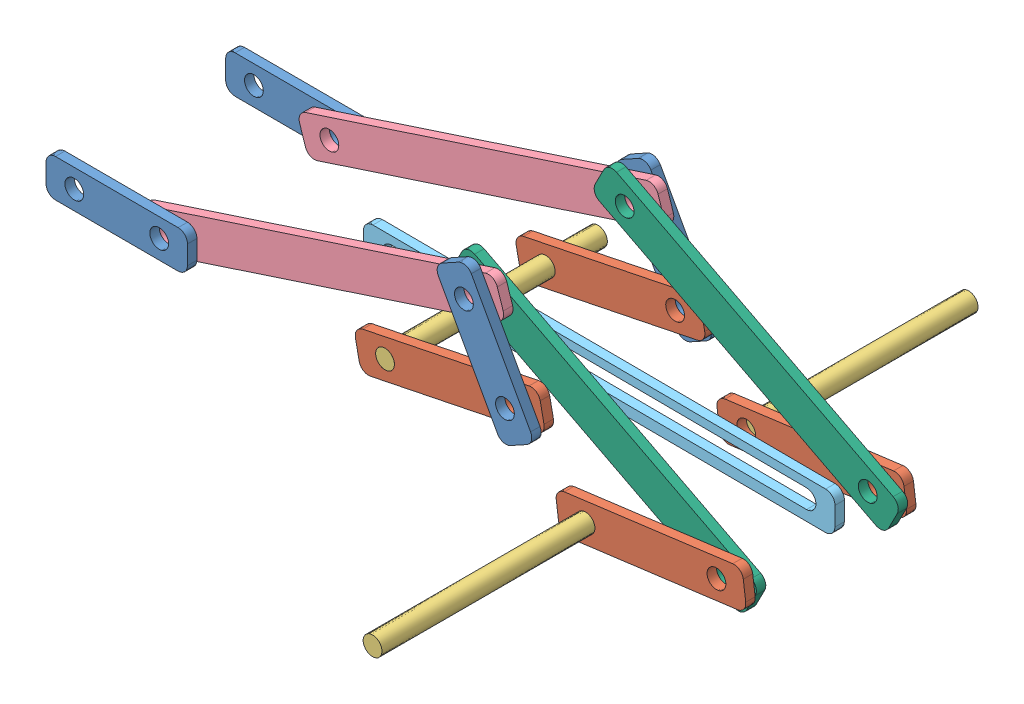
SolidWorks assembly new_ass, configuration Default. Lengths in mm.
Overall size (736.74 210.64 632.03).
16 component instances, 6 part files, 11 mates.
Components (placement in the parent):
- link1_new-1: link1_new [Default] at (825.2178 238.8003 -95.2164) x (0.483409 -0.875394 0) z (0 0 1) size (150 40 10)
- link2_new-1: link2_new [Default] at (957.4552 250.499 -85.2164) x (0.979728 0.20033 0) z (0 0 1) size (200 40 10)
- sli-1: sli [Default] at (759.4311 331.9248 -22.6838) x (0.228424 -0.973562 0) z (0 0 1) size (20 20 225.8)
- T link_new-1: T link_new [Default] at (737.609 273.8807 -85.2164) x (0.950313 0.311297 0) z (0 0 1) size (400 40 10)
- slider-1: slider [Default] at (944.9555 475.3871 -12.2849) x (-0.999987 0.005115 0) z (0 0 1) size (500 40 10)
- link1_new-2: link1_new [Default] at (614.9591 213.5241 -95.2164) x (0.999997 -0.00236 0) z (0 0 1) size (150 40 10)
- link1_new-3: link1_new [Default] at (614.9591 213.5241 95.2164) x (0.999997 -0.00236 0) z (0 0 1) size (150 40 10)
- T link_new-2: T link_new [Default] at (737.609 273.8807 85.2164) x (0.950313 0.311297 0) z (0 0 1) size (400 40 10)
- link2_new-2: link2_new [Default] at (957.4552 250.499 85.2164) x (0.979728 0.20033 0) z (0 0 1) size (200 40 10)
- link1_new-4: link1_new [Default] at (825.2178 238.8003 95.2164) x (0.483409 -0.875394 0) z (0 0 1) size (150 40 10)
- F link_new-1: F link_new [Default] at (948.9854 256.0848 75.2164) x (0.888813 -0.458271 0) z (0 0 1) size (350 40 10)
- link2_new-3: link2_new [Default] at (1162.7763 192.7024 85.2164) x (0.991607 0.129288 0) z (0 0 1) size (200 40 10)
- sli-3: sli [Default] at (984.4151 288.6899 203.1167) x (0.923944 -0.382528 0) z (0 0 1) size (20 20 225.8)
- link2_new-4: link2_new [Default] at (1162.7763 192.7024 -85.2164) x (0.991607 0.129288 0) z (0 0 1) size (200 40 10)
- F link_new-2: F link_new [Default] at (948.9854 256.0848 -75.2164) x (0.888813 -0.458271 0) z (0 0 1) size (350 40 10)
- sli-4: sli [Default] at (984.4151 288.6899 -203.1167) x (0.923944 -0.382528 0) z (0 0 1) size (20 20 225.8)
Mates (geometry in assembly coordinates):
- Width1: width: cylinder of slider-1; plane of sli-1 through (1114.2231 352.197 -7.2849) normal (-0.006526 -0.999979 0); cylinder of slider-1 through (764.7215 344.4776 90.2164) axis (0 0 -1) radius 10
- Slot2: slot: cylinder of sli-1 through (764.7215 344.4776 90.2164) axis (0 0 -1) radius 10; plane of slider-1 through (1114.2231 352.197 -7.2849) normal (-0.006526 -0.999979 0); cylinder of slider-1 through (1114.1579 342.1972 -7.2849) axis (0 0 -1) radius 10
- Concentric1: concentric aligned: cylinder of sli-1 through (764.7215 344.4776 90.2164) axis (0 0 -1) radius 10; cylinder of link2_new-2 through (764.7215 344.4776 90.2164) axis (0 0 -1) radius 10
- Coincident14: coincident aligned: circle of link1_new-3; circle of T link_new-2
- Coincident18: coincident aligned: circle of link2_new-2; circle of link1_new-4
- Coincident21: coincident aligned: circle of sli-1; circle of link2_new-2
- Coincident22: coincident aligned: circle of F link_new-1; circle of link2_new-3
- Coincident23: coincident aligned: circle of link2_new-3; circle of sli-3
- Coincident24: coincident aligned: circle of T link_new-2; circle of link1_new-4
- Coincident27: coincident aligned: circle of T link_new-2; circle of F link_new-1
- Tangent5: tangent anti-aligned: cylinder of sli-1 through (764.7215 344.4776 90.2164) axis (0 0 -1) radius 10; plane of slider-1 through (1114.2231 352.197 -7.2849) normal (-0.006526 -0.999979 0)
